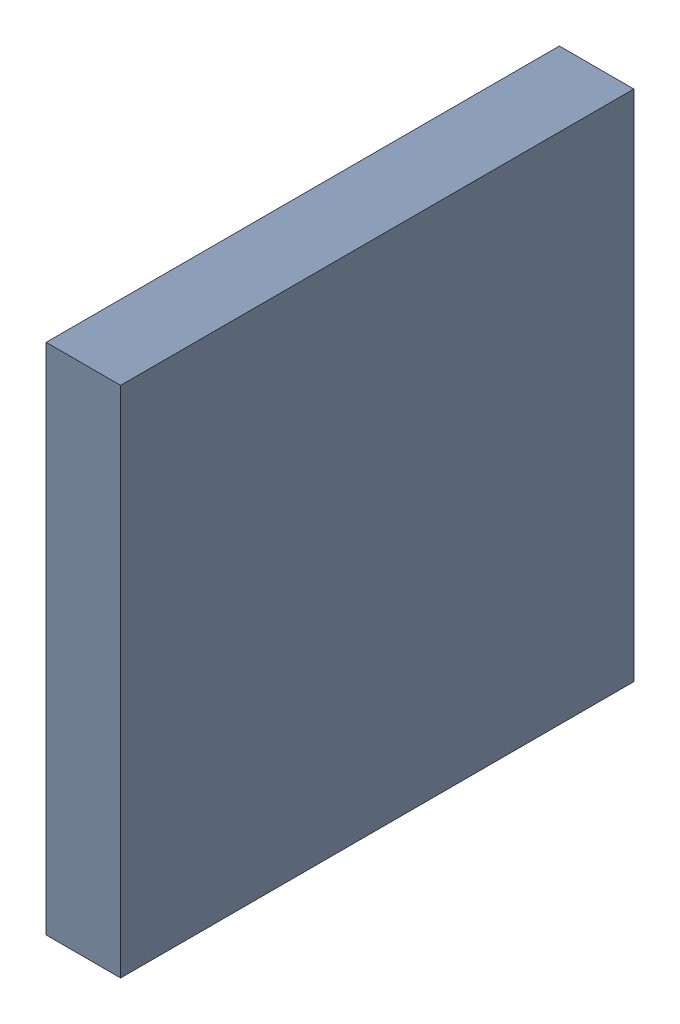
SolidWorks assembly D0, configuration Default. Lengths in mm.
Overall size (0.25 1.75 1.75).
4 component instances, 1 part files, 0 mates.
Components (placement in the parent):
- 6701982208-1:  [Default] at (27.7 14.8 0) (suppressed, hidden)
- 6327396160-1: 6327396160 [Default] at (4.2287 10.45 -1.7931) x (0 0 -1) z (1 0 0) size (1.75 1.75 0.25)
  - 6701982208-1:  [Default] at (27.7 14.8 0) (suppressed, hidden)
  - Extruded-21-1: Extruded-21 [Default] at origin size (1.75 1.75 0.25)
